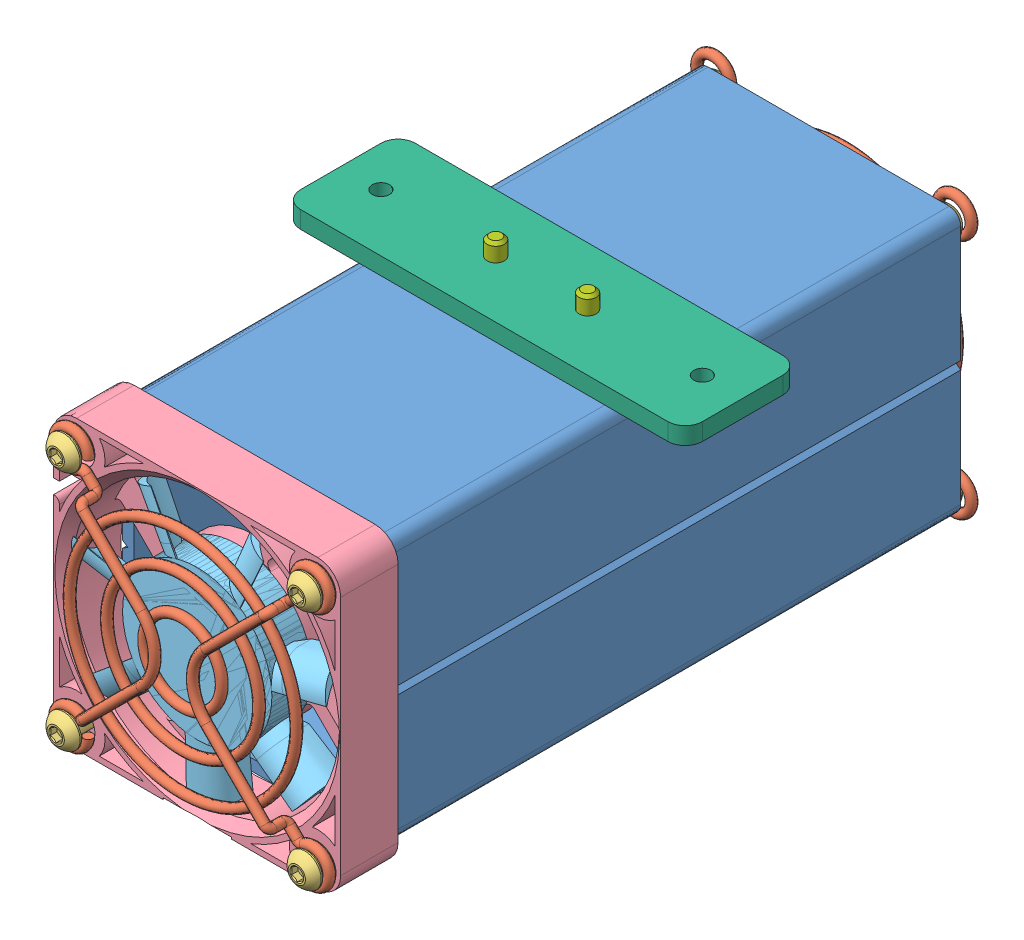
SolidWorks assembly laser driver all, configuration Default. Lengths in mm.
Overall size (70 56.43 120.4).
18 component instances, 8 part files, 29 mates.
Components (placement in the parent):
- laser driver box main body-1: laser driver box main body [Default] at (63.0779 83.2943 26.0047) x (1 0 0) z (0 -1 0) size (46 100 46)
- 50mm fan grill-1: 50mm fan grill [Default] at (63.0022 83.1988 136.0042) x (1 0 0) z (0 -1 0) size (49.4 5.46 49.4)
- Button Head Socket Cap Screw M3-1: Button Head Socket Cap Screw M3 [M3 x 12] at (84.0779 62.2943 126.0047) x (0 0 -1) z (1 0 0) size (13.72 5.7 5.7)
- Button Head Socket Cap Screw M3-2: Button Head Socket Cap Screw M3 [M3 x 12] at (42.0779 62.2943 126.0047) x (0 0 -1) z (1 0 0) size (13.72 5.7 5.7)
- Button Head Socket Cap Screw M3-3: Button Head Socket Cap Screw M3 [M3 x 12] at (42.0779 104.2943 126.0047) x (0 0 -1) z (1 0 0) size (13.72 5.7 5.7)
- Button Head Socket Cap Screw M3-4: Button Head Socket Cap Screw M3 [M3 x 12] at (84.0779 104.2943 126.0047) x (0 0 -1) z (1 0 0) size (13.72 5.7 5.7)
- fan_asm-2: fan_asm [Default] at (-332.7982 222.9958 136.0047) x (1 0 0) z (0 1 0) size (54.48 10.28 54.48)
  - fan_case-1: fan_case [Default] at origin size (50 10.1 50)
  - fan-1: fan [Default] at (415.4421 3.5826 -113.9746) x (0.605351 0 0.795959) z (0.795959 0 -0.605351) size (45.4 7.28 44.65)
- laser driver box mouinting-1: laser driver box mouinting [Default] at (63.0779 106.2943 76.0047) size (70 3 20)
- Threaded spacer,mild steel,M3x10mm,MF-1: Threaded spacer,mild steel,M3x10mm,MF [Default] at (55.0779 94.2943 76.0047) x (0.924886 0 -0.380244) z (0 1 0) size (5 5.77 18)
- Threaded spacer,mild steel,M3x10mm,MF-2: Threaded spacer,mild steel,M3x10mm,MF [Default] at (71.0779 94.2943 76.0047) x (0.924886 0 -0.380244) z (0 1 0) size (5 5.77 18)
- laser driver-1: laser driver [Default] at (61.0703 92.6943 71.0647) x (0 0 1) z (-1 0 0) size (49.14 1.6 33.19)
- 50mm fan grill-3: 50mm fan grill [Default] at (63.1151 83.7042 25.8617) x (1 0 0) z (0 1 0) size (49.4 5.46 49.4)
- Button Head Socket Cap Screw M3-5: Button Head Socket Cap Screw M3 [M3 x 6] at (43.0779 63.2943 32.0047) x (0 0 1) z (-1 0 0) size (7.72 5.7 5.7)
- Button Head Socket Cap Screw M3-6: Button Head Socket Cap Screw M3 [M3 x 6] at (43.0779 103.2943 32.0047) x (0 0 1) z (-0.67555 -0.737314 0) size (7.72 5.7 5.7)
- Button Head Socket Cap Screw M3-7: Button Head Socket Cap Screw M3 [M3 x 6] at (83.0779 103.2943 32.0047) x (0 0 1) z (-1 0 0) size (7.72 5.7 5.7)
- Button Head Socket Cap Screw M3-8: Button Head Socket Cap Screw M3 [M3 x 6] at (83.0779 63.2943 32.0047) x (0 0 1) z (-1 0 0) size (7.72 5.7 5.7)
Mates (geometry in assembly coordinates):
- Concentric91: concentric anti-aligned: cylinder of Button Head Socket Cap Screw M3-4 through (84.0779 104.2943 138.0047) axis (0 0 -1) radius 1.5; cylinder of fan_asm-2/fan_case-1 through (84.0779 104.2943 126.0047) axis (0 0 1) radius 1.75
- Concentric101: concentric anti-aligned: cylinder of Button Head Socket Cap Screw M3-1 through (84.0779 62.2943 138.0047) axis (0 0 -1) radius 1.5; cylinder of fan_asm-2/fan_case-1 through (84.0779 62.2943 126.0047) axis (0 0 1) radius 1.75
- Concentric111: concentric anti-aligned: cylinder of Button Head Socket Cap Screw M3-3 through (42.0779 104.2943 138.0047) axis (0 0 -1) radius 1.5; cylinder of fan_asm-2/fan_case-1 through (42.0779 104.2943 126.0047) axis (0 0 1) radius 1.75
- Concentric121: concentric anti-aligned: cylinder of Button Head Socket Cap Screw M3-2 through (42.0779 62.2943 138.0047) axis (0 0 -1) radius 1.5; cylinder of fan_asm-2/fan_case-1 through (42.0779 62.2943 126.0047) axis (0 0 1) radius 1.75
- Coincident121: coincident anti-aligned: plane of laser driver box main body-1 through (63.0779 83.2943 126.0047) normal (0 0 1); plane of fan_asm-2/fan_case-1 through (63.0779 83.2943 126.0047) normal (0 0 -1)
- Width11: width anti-aligned: plane of laser driver box main body-1 through (40.0779 106.2943 126.0047) normal (0 1 0); plane of laser driver box main body-1 through (40.0779 60.2943 126.0047) normal (0 -1 0); plane of fan_asm-2/fan_case-1 through (57.0779 58.2943 126.0047) normal (0 -1 0); plane of fan_asm-2/fan_case-1 through (42.0779 108.2943 126.0047) normal (0 1 0)
- Width21: width anti-aligned: plane of laser driver box main body-1 through (40.0779 82.6927 126.0047) normal (-1 0 0); plane of laser driver box main body-1 through (86.0779 82.582 126.0047) normal (1 0 0); plane of fan_asm-2/fan_case-1 through (88.0779 104.2943 126.0047) normal (1 0 0); plane of fan_asm-2/fan_case-1 through (38.0779 62.2943 126.0047) normal (-1 0 0)
- Lock11: lock: unknown of 50mm fan grill-1; unknown of fan_asm-2/fan_case-1
- Lock21: lock: unknown of 50mm fan grill-1; unknown of fan_asm-2/fan_case-1
- Concentric131: concentric anti-aligned: cylinder of laser driver box main body-1 through (55.0779 60.2933 76.0047) axis (0 1 0) radius 1.5; cylinder of laser driver box mouinting-1 through (55.0779 109.2943 76.0047) axis (0 -1 0) radius 1.5
- Concentric141: concentric anti-aligned: cylinder of laser driver box main body-1 through (71.0779 60.2933 76.0047) axis (0 1 0) radius 1.5; cylinder of laser driver box mouinting-1 through (71.0779 109.2943 76.0047) axis (0 -1 0) radius 1.5
- Coincident141: coincident anti-aligned: plane of laser driver box main body-1 through (40.0779 106.2943 126.0047) normal (0 1 0); plane of laser driver box mouinting-1 through (95.0779 106.2943 69.0047) normal (0 -1 0)
- Coincident151: coincident anti-aligned: plane of laser driver box main body-1 through (44.1959 104.2943 126.0047) normal (0 -1 0); plane of Threaded spacer,mild steel,M3x10mm,MF-2 through (69.5939 104.2943 78.9698) normal (0 1 0)
- Coincident161: coincident anti-aligned: plane of laser driver box main body-1 through (44.1959 104.2943 126.0047) normal (0 -1 0); plane of Threaded spacer,mild steel,M3x10mm,MF-1 through (53.5939 104.2943 78.9698) normal (0 1 0)
- Concentric151: concentric aligned: cylinder of laser driver box main body-1 through (71.0779 60.2933 76.0047) axis (0 1 0) radius 1.5; cylinder of Threaded spacer,mild steel,M3x10mm,MF-2 through (71.0779 111.7943 76.0047) axis (0 1 0) radius 1.5
- Concentric161: concentric aligned: cylinder of laser driver box main body-1 through (55.0779 60.2933 76.0047) axis (0 1 0) radius 1.5; cylinder of Threaded spacer,mild steel,M3x10mm,MF-1 through (55.0779 111.7943 76.0047) axis (0 1 0) radius 1.5
- Coincident171: coincident anti-aligned: plane of Threaded spacer,mild steel,M3x10mm,MF-2 through (69.8765 94.2943 79.6573) normal (0 -1 0); plane of laser driver-1 through (61.0703 94.2943 71.0647) normal (0 1 0)
- Coincident181: coincident anti-aligned: plane of Threaded spacer,mild steel,M3x10mm,MF-1 through (53.8765 94.2943 79.6573) normal (0 -1 0); plane of laser driver-1 through (61.0703 94.2943 71.0647) normal (0 1 0)
- Concentric191: concentric anti-aligned: cylinder of Threaded spacer,mild steel,M3x10mm,MF-2 through (71.1253 102.7943 76.0047) axis (0 1 0) radius 1.5; cylinder of laser driver-1 through (71.1253 94.2943 76.0047) axis (0 -1 0) radius 1.7
- Concentric22: concentric anti-aligned: cylinder of Threaded spacer,mild steel,M3x10mm,MF-1 through (55.1253 102.7943 76.0047) axis (0 1 0) radius 1.5; cylinder of laser driver-1 through (55.1253 94.2943 76.0047) axis (0 -1 0) radius 1.7
- Concentric1921: concentric anti-aligned: cylinder of laser driver box main body-1 through (43.0779 63.2943 126.0047) axis (0 0 -1) radius 1; cylinder of Button Head Socket Cap Screw M3-5 through (43.0779 63.2943 26.0047) axis (0 0 1) radius 2.85
- Coincident1821: coincident anti-aligned: plane of laser driver box main body-1 through (63.0779 83.2943 26.0047) normal (0 0 -1); plane of Button Head Socket Cap Screw M3-5 through (43.0779 66.1443 26.0047) normal (0 0 1)
- Concentric1931: concentric anti-aligned: cylinder of laser driver box main body-1 through (43.0779 103.2943 126.0047) axis (0 0 -1) radius 1; cylinder of Button Head Socket Cap Screw M3-6 through (43.0779 103.2943 26.0047) axis (0 0 1) radius 2.85
- Coincident1831: coincident anti-aligned: plane of laser driver box main body-1 through (63.0779 83.2943 26.0047) normal (0 0 -1); plane of Button Head Socket Cap Screw M3-6 through (40.9765 105.2196 26.0047) normal (0 0 1)
- Concentric1941: concentric anti-aligned: cylinder of laser driver box main body-1 through (83.0779 103.2943 126.0047) axis (0 0 -1) radius 1; cylinder of Button Head Socket Cap Screw M3-7 through (83.0779 103.2943 26.0047) axis (0 0 1) radius 2.85
- Coincident1841: coincident anti-aligned: plane of laser driver box main body-1 through (63.0779 83.2943 26.0047) normal (0 0 -1); plane of Button Head Socket Cap Screw M3-7 through (83.0779 106.1443 26.0047) normal (0 0 1)
- Concentric1951: concentric anti-aligned: cylinder of laser driver box main body-1 through (83.0779 63.2943 126.0047) axis (0 0 -1) radius 1; cylinder of Button Head Socket Cap Screw M3-8 through (83.0779 63.2943 26.0047) axis (0 0 1) radius 2.85
- Coincident1851: coincident anti-aligned: plane of laser driver box main body-1 through (63.0779 83.2943 26.0047) normal (0 0 -1); plane of Button Head Socket Cap Screw M3-8 through (83.0779 66.1443 26.0047) normal (0 0 1)
- Lock22: lock: unknown of laser driver box main body-1; unknown of 50mm fan grill-3
